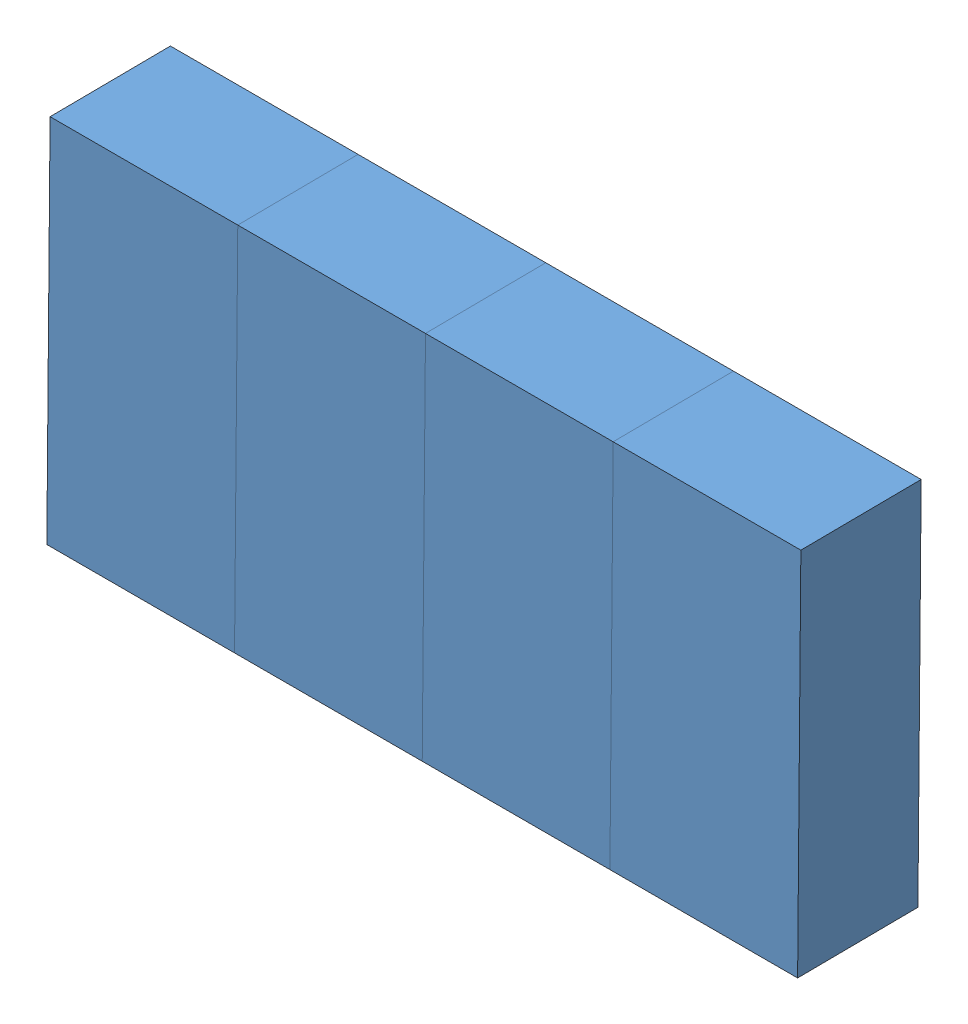
SolidWorks assembly Heat Treat Asm Back, configuration Default. Lengths in mm.
Overall size (462.63 234.01 79.01).
4 component instances, 1 part files, 9 mates.
Components (placement in the parent):
- Brick-Sharp-1: Brick-Sharp [Default] at (91.3299 124.3408 170.7235) x (-0.008727 -0.999962 0) z (-0.999924 0.008726 0.008727) size (230 75 115)
- Brick-Sharp-2: Brick-Sharp [Default] at (206.3211 123.3373 169.7199) x (0.008727 0.999962 0) z (-0.999924 0.008726 0.008727) size (230 75 115)
- Brick-Sharp-3: Brick-Sharp [Default] at (436.3036 121.3303 167.7128) x (-0.008727 -0.999962 0) z (0.999924 -0.008726 -0.008727) size (230 75 115)
- Brick-Sharp-4: Brick-Sharp [Default] at (321.3124 122.3338 168.7164) x (-0.008727 -0.999962 0) z (0.999924 -0.008726 -0.008727) size (230 75 115)
Mates (geometry in assembly coordinates):
- Coincident2: coincident: plane of Brick-Sharp-1 through (150.1563 238.8318 207.7203) normal (0.999924 -0.008726 -0.008727); plane of Brick-Sharp-2 through (147.4947 8.8463 132.7231) normal (-0.999924 0.008726 0.008727)
- Coincident3: coincident: line of Brick-Sharp-1 through (148.1492 8.8406 207.7203) axis (0.008727 0.999962 0); plane of Brick-Sharp-2 through (206.6484 123.3345 207.2185) normal (0.008726 -0.000076 0.999962)
- Coincident4: coincident: plane of Brick-Sharp-1 through (148.1492 8.8406 207.7203) normal (-0.008727 -0.999962 0); line of Brick-Sharp-2 through (147.4947 8.8463 132.7231) axis (0.008726 -0.000076 0.999962)
- Coincident5: coincident: plane of Brick-Sharp-2 through (262.486 7.8428 131.7196) normal (0.999924 -0.008726 -0.008727); plane of Brick-Sharp-4 through (264.4931 237.834 131.7196) normal (-0.999924 0.008726 0.008727)
- Coincident6: coincident: line of Brick-Sharp-2 through (264.4931 237.834 131.7196) axis (0.008726 -0.000076 0.999962); line of Brick-Sharp-4 through (264.4931 237.834 131.7196) axis (0.008726 -0.000076 0.999962)
- Coincident7: coincident anti-aligned: line of Brick-Sharp-2 through (265.1475 237.8283 206.7167) axis (-0.008727 -0.999962 0); line of Brick-Sharp-4 through (263.1404 7.8371 206.7167) axis (0.008727 0.999962 0)
- Coincident8: coincident: plane of Brick-Sharp-3 through (379.4843 236.8305 130.716) normal (-0.999924 0.008726 0.008727); plane of Brick-Sharp-4 through (379.4843 236.8305 130.716) normal (0.999924 -0.008726 -0.008727)
- Coincident9: coincident: line of Brick-Sharp-3 through (379.4843 236.8305 130.716) axis (0.008726 -0.000076 0.999962); line of Brick-Sharp-4 through (379.4843 236.8305 130.716) axis (0.008726 -0.000076 0.999962)
- Coincident10: coincident anti-aligned: line of Brick-Sharp-3 through (377.4772 6.8393 130.716) axis (0.008727 0.999962 0); line of Brick-Sharp-4 through (379.4843 236.8305 130.716) axis (-0.008727 -0.999962 0)
